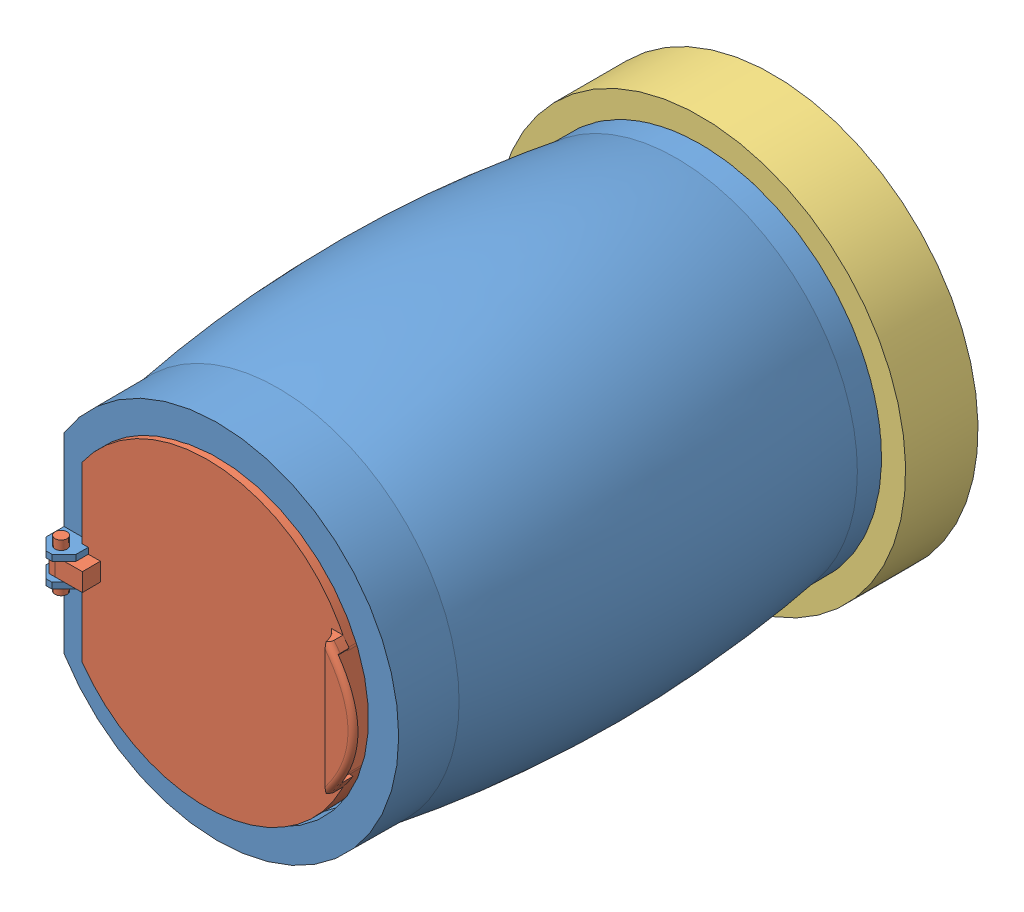
SolidWorks assembly Assem1, configuration Default. Lengths in mm.
Overall size (47.3 49.72 48.5).
6 component instances, 6 part files, 7 mates.
Components (placement in the parent):
- Part3-1: Part3 [Default] at (1.7347 -23.0405 28.6622) size (30.4 32.61 43.5)
- Part4-1: Part4 [Default] at (1.2305 -23.1648 67.0943) x (0.999981 0 -0.006106) z (-0.006106 0 -0.999981) size (25.34 25 3.5)
- Part5-1: Part5 [Default] at (1.7347 -23.0405 20.6622) x (0.90624 -0.422763 0) z (-0.422763 -0.90624 0) size (34 6 39)
- Part6-1: Part6 [Default] at (1.7347 -23.0405 22.6622) size (18 18 2)
- Part7-1: Part7 [Default] at (1.7347 -23.0405 24.6622) size (18 18 1.5)
- Part8-1: Part8 [Default] at (1.7347 -23.0405 25.6622) size (22 22 35.01)
Mates (geometry in assembly coordinates):
- Concentric2: concentric anti-aligned: cylinder of Part3-1 through (-9.7432 -21.842 68.1622) axis (0 -1 0) radius 0.5; cylinder of Part4-1 through (-9.7432 -25.092 68.1622) axis (0 1 0) radius 0.5
- Coincident2: coincident anti-aligned: plane of Part3-1 through (-10.991 -23.842 66.6622) normal (0 1 0); plane of Part4-1 through (-7.4902 -23.842 68.6475) normal (0 -1 0)
- Coincident3: coincident aligned: circle of Part5-1; circle of Part6-1
- Concentric4: concentric anti-aligned: cylinder of Part5-1 through (1.7347 -23.0405 22.6622) axis (0 0 1) radius 9; cylinder of Part7-1 through (1.7347 -23.0405 26.1622) axis (0 0 -1) radius 9
- Coincident4: coincident anti-aligned: plane of Part6-1 through (1.7347 -23.0405 24.6622) normal (0 0 1); plane of Part7-1 through (1.7347 -23.0405 24.6622) normal (0 0 -1)
- Coincident5: coincident aligned: circle of Part5-1; circle of Part8-1
- Coincident6: coincident anti-aligned: circle of Part3-1; circle of Part5-1
